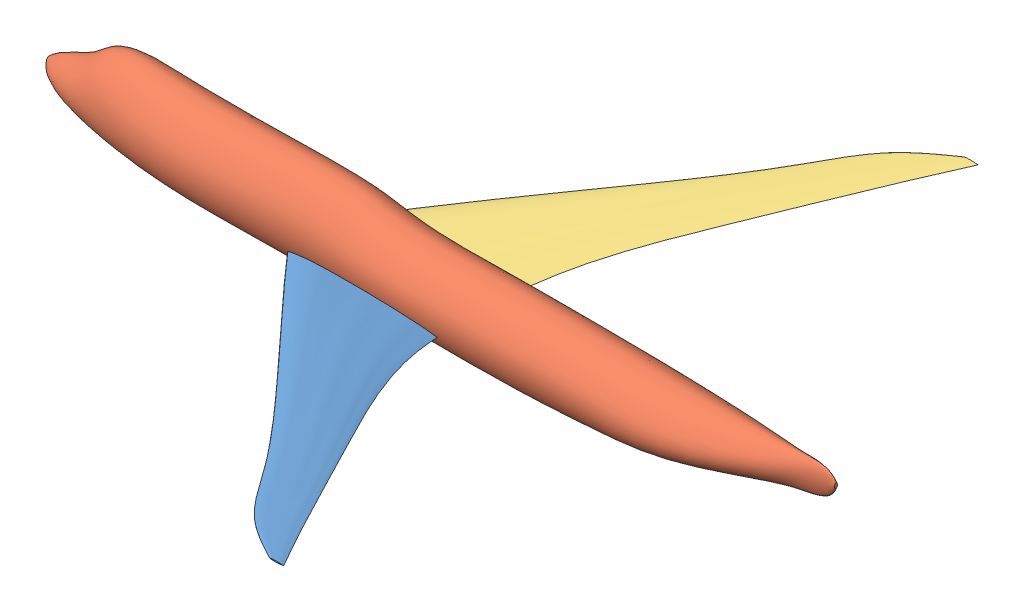
SolidWorks assembly Assem1, configuration Default. Lengths in mm.
Overall size (656 375 664.45).
3 component instances, 3 part files, 3 mates.
Components (placement in the parent):
- b747-8-left-wing-1: b747-8-left-wing [Default] at origin size (656 375 664.45)
- fuselage-1: fuselage [Default] at (-87.376 -2 -8) size (264.87 30.68 24.71)
- Mirrorb747-8-left-wing-3: Mirrorb747-8-left-wing [Default] at (0 0 -16) size (105.87 16.83 107.35)
Mates (geometry in assembly coordinates):
- Coincident1: coincident anti-aligned: plane of b747-8-left-wing-1 through (24.3912 -9.0623 0) normal (0 0 -1); plane of fuselage-1 through (-87.376 -2 0) normal (0 0 1)
- Coincident2: coincident aligned: plane of fuselage-1 through (-87.376 0 -8) normal (0 1 0)
- Coincident3: coincident aligned: plane of fuselage-1 through (0 -2 -8) normal (1 0 0)
